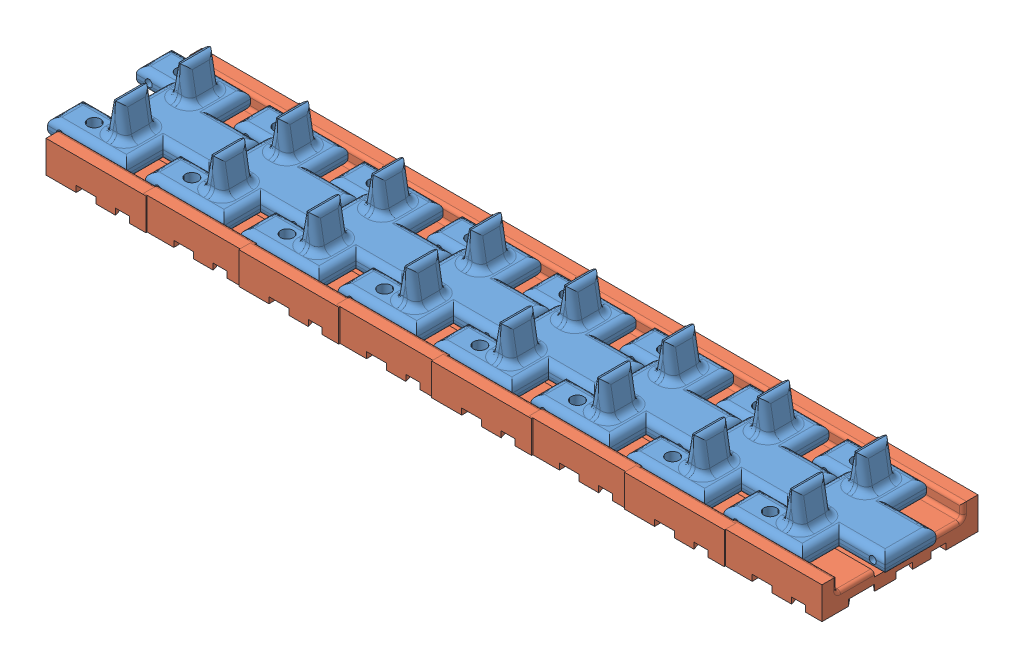
SolidWorks assembly AV_Comp_Mech_1_1_9_WholeTrack, configuration Default. Lengths in mm.
Overall size (225.46 19.36 44.35).
20 component instances, 2 part files, 26 mates.
Components (placement in the parent):
- AV_Comp_Mech_1_1_6_TrackAssembly-1: AV_Comp_Mech_1_1_6_TrackAssembly [Default] at (-66.8469 2.2745 -10.8813) size (35.18 19.36 44)
  - AV_Comp_Mech_1_1_3_TracksV3-1: AV_Comp_Mech_1_1_3_TracksV3 [Default] at (9.2421 14.1316 25.58) size (35.18 14.36 35)
  - AV_Comp_Mech_1_1_5_OuterTrack_TPU_2-1: AV_Comp_Mech_1_1_5_OuterTrack_TPU_2 [Default] at (12.2777 11.1316 25.5805) x (1 0 0) z (0 1 0) size (28.18 44 9)
- AV_Comp_Mech_1_1_3_TracksV3-1: AV_Comp_Mech_1_1_3_TracksV3 [Default] at (-84.787 16.4061 15.0487) size (35.18 14.36 35)
- AV_Comp_Mech_1_1_5_OuterTrack_TPU_2-1: AV_Comp_Mech_1_1_5_OuterTrack_TPU_2 [Default] at (-81.7514 13.4061 15.0492) x (1 0 0) z (0 1 0) size (28.18 44 9)
- AV_Comp_Mech_1_1_5_OuterTrack_TPU_2-3: AV_Comp_Mech_1_1_5_OuterTrack_TPU_2 [Default] at (-136.1157 13.4061 15.0492) x (1 0 0) z (0 1 0) size (28.18 44 9)
- AV_Comp_Mech_1_1_3_TracksV3-3: AV_Comp_Mech_1_1_3_TracksV3 [Default] at (-139.1513 16.4061 15.0487) size (35.18 14.36 35)
- AV_Comp_Mech_1_1_6_TrackAssembly-3: AV_Comp_Mech_1_1_6_TrackAssembly [Default] at (-121.2112 2.2745 -10.8813) size (35.18 19.36 44)
  - AV_Comp_Mech_1_1_3_TracksV3-1: AV_Comp_Mech_1_1_3_TracksV3 [Default] at (9.2421 14.1316 25.58) size (35.18 14.36 35)
  - AV_Comp_Mech_1_1_5_OuterTrack_TPU_2-1: AV_Comp_Mech_1_1_5_OuterTrack_TPU_2 [Default] at (12.2777 11.1316 25.5805) x (1 0 0) z (0 1 0) size (28.18 44 9)
- AV_Comp_Mech_1_1_5_OuterTrack_TPU_2-4: AV_Comp_Mech_1_1_5_OuterTrack_TPU_2 [Default] at (-190.48 13.4061 15.0492) x (1 0 0) z (0 1 0) size (28.18 44 9)
- AV_Comp_Mech_1_1_5_OuterTrack_TPU_2-5: AV_Comp_Mech_1_1_5_OuterTrack_TPU_2 [Default] at (-244.8444 13.4061 15.0492) x (1 0 0) z (0 1 0) size (28.18 44 9)
- AV_Comp_Mech_1_1_3_TracksV3-4: AV_Comp_Mech_1_1_3_TracksV3 [Default] at (-247.8799 16.4061 15.0487) size (35.18 14.36 35)
- AV_Comp_Mech_1_1_6_TrackAssembly-4: AV_Comp_Mech_1_1_6_TrackAssembly [Default] at (-229.9399 2.2745 -10.8813) size (35.18 19.36 44)
  - AV_Comp_Mech_1_1_3_TracksV3-1: AV_Comp_Mech_1_1_3_TracksV3 [Default] at (9.2421 14.1316 25.58) size (35.18 14.36 35)
  - AV_Comp_Mech_1_1_5_OuterTrack_TPU_2-1: AV_Comp_Mech_1_1_5_OuterTrack_TPU_2 [Default] at (12.2777 11.1316 25.5805) x (1 0 0) z (0 1 0) size (28.18 44 9)
- AV_Comp_Mech_1_1_3_TracksV3-5: AV_Comp_Mech_1_1_3_TracksV3 [Default] at (-193.5156 16.4061 15.0487) size (35.18 14.36 35)
- AV_Comp_Mech_1_1_6_TrackAssembly-5: AV_Comp_Mech_1_1_6_TrackAssembly [Default] at (-175.5755 2.2745 -10.8813) size (35.18 19.36 44)
  - AV_Comp_Mech_1_1_3_TracksV3-1: AV_Comp_Mech_1_1_3_TracksV3 [Default] at (9.2421 14.1316 25.58) size (35.18 14.36 35)
  - AV_Comp_Mech_1_1_5_OuterTrack_TPU_2-1: AV_Comp_Mech_1_1_5_OuterTrack_TPU_2 [Default] at (12.2777 11.1316 25.5805) x (1 0 0) z (0 1 0) size (28.18 44 9)
Mates (geometry in assembly coordinates):
- Coincident1: coincident aligned: circle of AV_Comp_Mech_1_1_3_TracksV3-1; circle of AV_Comp_Mech_1_1_5_OuterTrack_TPU_2-1
- Parallel1: parallel anti-aligned: plane of AV_Comp_Mech_1_1_3_TracksV3-1 through (-99.7783 21.4061 -2.3508) normal (0 0 -1); plane of AV_Comp_Mech_1_1_5_OuterTrack_TPU_2-1 through (-58.8414 21.4061 -2.7008) normal (0 0 1)
- Coincident3: coincident anti-aligned: plane of AV_Comp_Mech_1_1_6_TrackAssembly-1/AV_Comp_Mech_1_1_3_TracksV3-1 through (-67.0962 21.4061 22.2992) normal (0 0 -1); plane of AV_Comp_Mech_1_1_3_TracksV3-1 through (-64.5962 21.4061 22.2992) normal (0 0 1)
- Coincident7: coincident anti-aligned: line of AV_Comp_Mech_1_1_6_TrackAssembly-1/AV_Comp_Mech_1_1_3_TracksV3-1 through (-64.5962 19.4061 22.2992) axis (0 0 -1); line of AV_Comp_Mech_1_1_3_TracksV3-1 through (-64.5962 19.4061 7.9992) axis (0 0 1)
- Coincident8: coincident anti-aligned: line of AV_Comp_Mech_1_1_6_TrackAssembly-1/AV_Comp_Mech_1_1_3_TracksV3-1 through (-64.5962 18.4061 7.2992) axis (0 0 1); line of AV_Comp_Mech_1_1_3_TracksV3-1 through (-64.5962 18.4061 22.2992) axis (0 0 -1)
- Coincident9: coincident anti-aligned: line of AV_Comp_Mech_1_1_3_TracksV3-3 through (-118.9605 18.4061 22.2992) axis (0 0 -1); line of AV_Comp_Mech_1_1_6_TrackAssembly-3/AV_Comp_Mech_1_1_3_TracksV3-1 through (-118.9605 18.4061 7.2992) axis (0 0 1)
- Parallel3: parallel anti-aligned: plane of AV_Comp_Mech_1_1_5_OuterTrack_TPU_2-3 through (-113.2057 21.4061 -2.7008) normal (0 0 1); plane of AV_Comp_Mech_1_1_3_TracksV3-3 through (-154.1427 21.4061 -2.3508) normal (0 0 -1)
- Coincident10: coincident anti-aligned: plane of AV_Comp_Mech_1_1_3_TracksV3-3 through (-118.9605 21.4061 22.2992) normal (0 0 1); plane of AV_Comp_Mech_1_1_6_TrackAssembly-3/AV_Comp_Mech_1_1_3_TracksV3-1 through (-121.4605 21.4061 22.2992) normal (0 0 -1)
- Coincident11: coincident aligned: circle of AV_Comp_Mech_1_1_5_OuterTrack_TPU_2-3; circle of AV_Comp_Mech_1_1_3_TracksV3-3
- Coincident12: coincident anti-aligned: line of AV_Comp_Mech_1_1_3_TracksV3-3 through (-118.9605 19.4061 7.9992) axis (0 0 1); line of AV_Comp_Mech_1_1_6_TrackAssembly-3/AV_Comp_Mech_1_1_3_TracksV3-1 through (-118.9605 19.4061 22.2992) axis (0 0 -1)
- Coincident13: coincident anti-aligned: line of AV_Comp_Mech_1_1_3_TracksV3-1 through (-91.7783 18.4061 7.6492) axis (0 0 1); line of AV_Comp_Mech_1_1_6_TrackAssembly-3/AV_Comp_Mech_1_1_3_TracksV3-1 through (-91.7783 18.4061 21.9492) axis (0 0 -1)
- Coincident16: coincident anti-aligned: line of AV_Comp_Mech_1_1_3_TracksV3-1 through (-91.7783 19.4061 7.6492) axis (-1 0 0); line of AV_Comp_Mech_1_1_6_TrackAssembly-3/AV_Comp_Mech_1_1_3_TracksV3-1 through (-94.4123 19.4061 7.6492) axis (1 0 0)
- Coincident17: coincident anti-aligned: line of AV_Comp_Mech_1_1_3_TracksV3-5 through (-173.2994 17.2315 23.0101) axis (0 0 -1); line of AV_Comp_Mech_1_1_6_TrackAssembly-5/AV_Comp_Mech_1_1_3_TracksV3-1 through (-173.2994 17.2315 8.0101) axis (0 0 1)
- Coincident18: coincident anti-aligned: line of AV_Comp_Mech_1_1_6_TrackAssembly-4/AV_Comp_Mech_1_1_3_TracksV3-1 through (-203.1309 16.9421 8.3601) axis (0.999066 0.043212 0); line of AV_Comp_Mech_1_1_3_TracksV3-5 through (-200.4994 17.0559 8.3601) axis (-0.999066 -0.043212 0)
- Parallel5: parallel anti-aligned: plane of AV_Comp_Mech_1_1_5_OuterTrack_TPU_2-4 through (-167.6797 20.4773 -1.9899) normal (0 0 1); plane of AV_Comp_Mech_1_1_3_TracksV3-5 through (-208.5784 18.7084 -1.6399) normal (0 0 -1)
- Coincident19: coincident anti-aligned: plane of AV_Comp_Mech_1_1_3_TracksV3-5 through (-173.4291 20.2287 23.0101) normal (0 0 1); plane of AV_Comp_Mech_1_1_6_TrackAssembly-5/AV_Comp_Mech_1_1_3_TracksV3-1 through (-175.9267 20.1206 23.0101) normal (0 0 -1)
- Coincident20: coincident aligned: circle of AV_Comp_Mech_1_1_5_OuterTrack_TPU_2-4; circle of AV_Comp_Mech_1_1_3_TracksV3-5
- Coincident21: coincident anti-aligned: line of AV_Comp_Mech_1_1_3_TracksV3-5 through (-173.3426 18.2305 8.7101) axis (0 0 1); line of AV_Comp_Mech_1_1_6_TrackAssembly-5/AV_Comp_Mech_1_1_3_TracksV3-1 through (-173.3426 18.2305 23.0101) axis (0 0 -1)
- Coincident22: coincident aligned: circle of AV_Comp_Mech_1_1_5_OuterTrack_TPU_2-5; circle of AV_Comp_Mech_1_1_3_TracksV3-4
- Coincident23: coincident anti-aligned: line of AV_Comp_Mech_1_1_3_TracksV3-4 through (-227.6562 15.8813 8.7101) axis (0 0 1); line of AV_Comp_Mech_1_1_6_TrackAssembly-4/AV_Comp_Mech_1_1_3_TracksV3-1 through (-227.6562 15.8813 23.0101) axis (0 0 -1)
- Coincident24: coincident anti-aligned: line of AV_Comp_Mech_1_1_3_TracksV3-4 through (-227.613 14.8823 23.0101) axis (0 0 -1); line of AV_Comp_Mech_1_1_6_TrackAssembly-4/AV_Comp_Mech_1_1_3_TracksV3-1 through (-227.613 14.8823 8.0101) axis (0 0 1)
- Coincident25: coincident anti-aligned: plane of AV_Comp_Mech_1_1_3_TracksV3-4 through (-227.7426 17.8795 23.0101) normal (0 0 1); plane of AV_Comp_Mech_1_1_6_TrackAssembly-4/AV_Comp_Mech_1_1_3_TracksV3-1 through (-230.2403 17.7714 23.0101) normal (0 0 -1)
- Parallel6: parallel anti-aligned: plane of AV_Comp_Mech_1_1_5_OuterTrack_TPU_2-5 through (-221.9932 18.1281 -1.9899) normal (0 0 1); plane of AV_Comp_Mech_1_1_3_TracksV3-4 through (-262.8919 16.3592 -1.6399) normal (0 0 -1)
- Coincident26: coincident anti-aligned: line of AV_Comp_Mech_1_1_6_TrackAssembly-4/AV_Comp_Mech_1_1_3_TracksV3-1 through (-200.4562 16.0569 22.6601) axis (0 0 -1); line of AV_Comp_Mech_1_1_3_TracksV3-5 through (-200.4562 16.0569 8.3601) axis (0 0 1)
- Coincident27: coincident anti-aligned: line of AV_Comp_Mech_1_1_3_TracksV3-3 through (-146.1427 18.4061 7.6492) axis (0 0 1); line of AV_Comp_Mech_1_1_6_TrackAssembly-5/AV_Comp_Mech_1_1_3_TracksV3-1 through (-146.1427 18.4061 22.6601) axis (0 0 -1)
- Coincident28: coincident anti-aligned: line of AV_Comp_Mech_1_1_3_TracksV3-3 through (-146.1427 19.4061 7.6492) axis (-1 0 0); line of AV_Comp_Mech_1_1_6_TrackAssembly-5/AV_Comp_Mech_1_1_3_TracksV3-1 through (-148.7766 19.4061 7.6492) axis (1 0 0)
